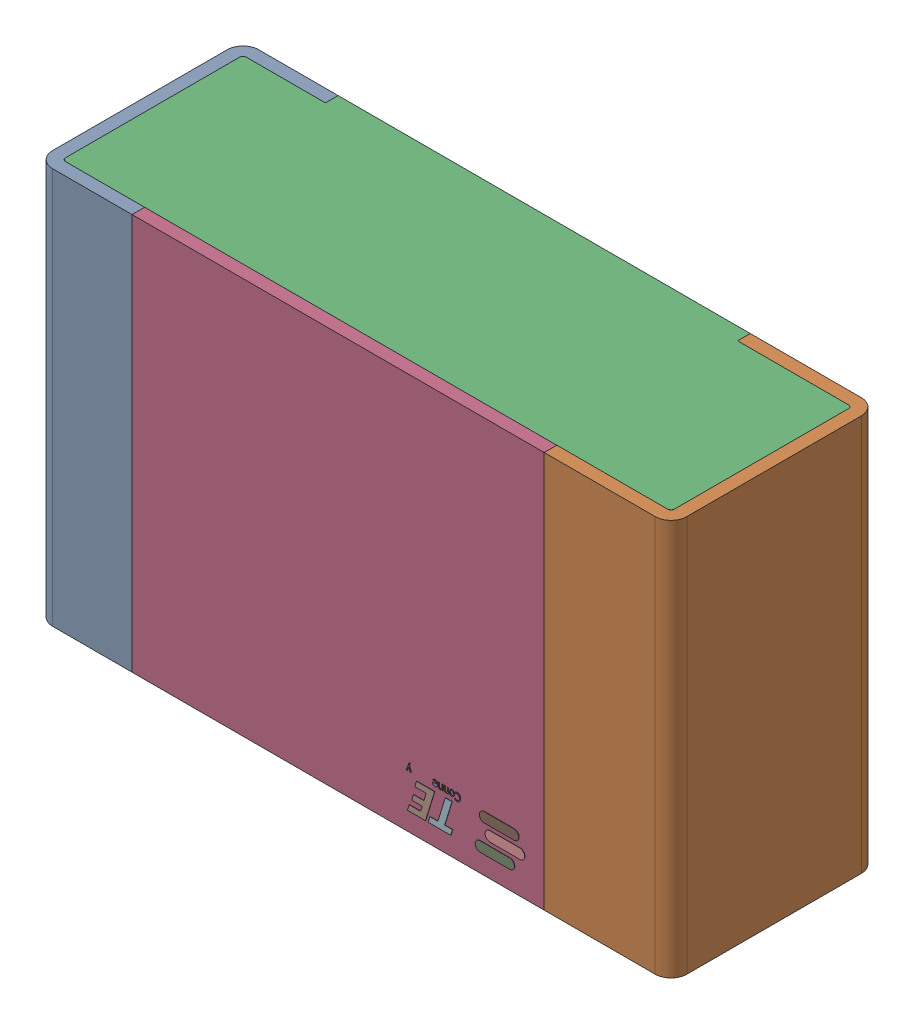
SolidWorks assembly R3.step, configuration Default. Lengths in mm.
Overall size (2 1.25 0.65).
5 component instances, 4 part files, 0 mates.
Components (placement in the parent):
- Res_TE_Connectivity_CPF0805B66R5E1_eec.step-1: Res_TE_Connectivity_CPF0805B66R5E1_eec.step [Default] at (47.117 32.639 0) x (-1 0 0) z (0 0 1) size (2 1.25 0.65)
  - 1.step-1: 1.step [Default] at origin size (2 1.25 0.65)
  - 2.step-1: 2.step [Default] at origin size (1.92 1.25 0.61)
  - 3.step-1: 3.step [Default] at origin size (1.3 1.25 0.04)
  - TE connectivity Logo 1 (2).step-1: TE connectivity Logo 1 (2).step [Default] at (5.4285 0.313 0.551) x (-1 0 0) z (0 0 1) size (0.37 0.13 0.11)
